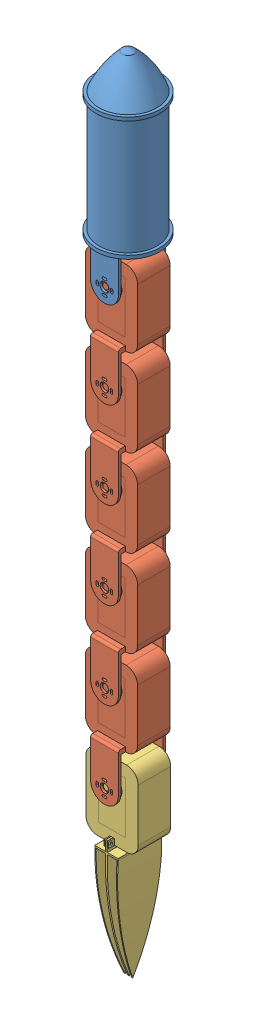
SolidWorks assembly bus_assembly_total_4, configuration 預設. Lengths in mm.
Overall size (647.03 670.77 55).
7 component instances, 3 part files, 24 mates.
Components (placement in the parent):
- base_link-2: base_link [預設] at (-200.3488 -8.0568 -97.9891) size (55 179.98 55)
- link1-1: link1 [預設] at (-286.3308 -349.3248 -5.4136) x (0 1 0) z (0 0 -1) size (45 107 40.5)
- link1-2: link1 [預設] at (-286.3308 -125.2248 -5.4136) x (0 1 0) z (0 0 -1) size (45 107 40.5)
- link1-3: link1 [預設] at (-286.3308 -199.9248 -5.4136) x (0 1 0) z (0 0 -1) size (45 107 40.5)
- link1-4: link1 [預設] at (-286.3308 -424.0248 -5.4136) x (0 1 0) z (0 0 -1) size (45 107 40.5)
- link1-5: link1 [預設] at (-286.3308 -274.6248 -5.4136) x (0 1 0) z (0 0 -1) size (45 107 40.5)
- link6-1: link6 [預設] at (-162.426 -442.9917 52.8279) x (0 1 0) z (0 0 -1) size (170.09 49.79 38.13)
Mates (geometry in assembly coordinates):
- 重合/共線/共點1: coincident: plane of base_link-2 through (-179.3308 -93.8197 20.2609) normal (0 0 -1); plane of link1-2 through (-179.3308 -93.8197 20.2609) normal (0 0 1)
- 重合/共線/共點2: coincident: plane of base_link-2 through (-179.3308 -93.8197 -16.2391) normal (0 0 1); plane of link1-2 through (-179.3308 -93.8197 -16.2391) normal (0 0 -1)
- 同軸心1: concentric: cylinder of base_link-2 through (-179.3308 -93.8197 20.2609) axis (0 0 1) radius 4; cylinder of link1-2 through (-179.3308 -93.8197 16.2609) axis (0 0 1) radius 4
- 重合/共線/共點3: coincident: plane of base_link-2 through (-180.3808 -86.6197 20.2609) normal (0 -1 0); plane of link1-2 through (-178.2808 -86.6197 16.2609) normal (0 -1 0)
- 重合/共線/共點4: coincident: plane of link1-2 through (-179.3308 -168.5197 20.2609) normal (0 0 -1); plane of link1-3 through (-179.3308 -168.5197 20.2609) normal (0 0 1)
- 重合/共線/共點5: coincident: plane of link1-2 through (-179.3308 -168.5197 -16.2391) normal (0 0 1); plane of link1-3 through (-179.3308 -168.5197 -16.2391) normal (0 0 -1)
- 同軸心2: concentric: cylinder of link1-2 through (-179.3308 -168.5197 -16.2391) axis (0 0 -1) radius 4; cylinder of link1-3 through (-179.3308 -168.5197 -17.2391) axis (0 0 1) radius 4
- 平行1: parallel: plane of link1-2 through (-172.2308 -169.5697 -16.2391) normal (-1 0 0); plane of link1-3 through (-172.1308 -169.5697 -17.2391) normal (-1 0 0)
- 重合/共線/共點7: coincident: plane of link1-3 through (-179.3308 -243.2197 -16.2391) normal (0 0 1); plane of link1-5 through (-179.3308 -243.2197 -16.2391) normal (0 0 -1)
- 重合/共線/共點8: coincident: plane of link1-3 through (-179.3308 -243.2197 20.2609) normal (0 0 -1); plane of link1-5 through (-179.3308 -243.2197 20.2609) normal (0 0 1)
- 同軸心3: concentric: cylinder of link1-3 through (-179.3308 -243.2197 22.2609) axis (0 0 -1) radius 3.7; cylinder of link1-5 through (-179.3308 -243.2197 16.2609) axis (0 0 1) radius 4
- 平行2: parallel: plane of link1-3 through (-178.2808 -236.1197 22.2609) normal (0 -1 0); plane of link1-5 through (-178.2808 -236.0197 16.2609) normal (0 -1 0)
- 重合/共線/共點10: coincident: plane of link1-1 through (-179.3308 -317.9197 20.2609) normal (0 0 1); plane of link1-5 through (-179.3308 -317.9197 20.2609) normal (0 0 -1)
- 重合/共線/共點11: coincident: plane of link1-1 through (-179.3308 -317.9197 -16.2391) normal (0 0 -1); plane of link1-5 through (-179.3308 -317.9197 -16.2391) normal (0 0 1)
- 同軸心4: concentric: cylinder of link1-1 through (-179.3308 -317.9197 16.2609) axis (0 0 1) radius 4; cylinder of link1-5 through (-179.3308 -317.9197 22.2609) axis (0 0 -1) radius 3.7
- 平行3: parallel: plane of link1-1 through (-178.2808 -310.7197 16.2609) normal (0 -1 0); plane of link1-5 through (-178.2808 -310.8197 22.2609) normal (0 -1 0)
- 重合/共線/共點13: coincident: plane of link1-1 through (-179.3308 -392.6197 20.2609) normal (0 0 -1); plane of link1-4 through (-179.3308 -392.6197 20.2609) normal (0 0 1)
- 重合/共線/共點14: coincident: plane of link1-1 through (-179.3308 -392.6197 -16.2391) normal (0 0 1); plane of link1-4 through (-179.3308 -392.6197 -16.2391) normal (0 0 -1)
- 同軸心5: concentric: cylinder of link1-1 through (-179.3308 -392.6197 -16.2391) axis (0 0 -1) radius 4; cylinder of link1-4 through (-179.3308 -392.6197 -17.2391) axis (0 0 1) radius 4
- 重合/共線/共點15: coincident: plane of link1-1 through (-178.2808 -397.8197 -16.2391) normal (0 -1 0); plane of link1-4 through (-178.2808 -397.8197 -17.2391) normal (0 -1 0)
- 重合/共線/共點16: coincident: plane of link1-4 through (-179.3308 -467.3197 20.2609) normal (0 0 -1); plane of link6-1 through (-179.3308 -467.3197 20.2609) normal (0 0 1)
- 平行4: parallel: plane of link1-4 through (-179.3308 -467.3197 -16.2391) normal (0 0 1); plane of link6-1 through (-179.3308 -467.3197 -16.7391) normal (0 0 -1)
- 同軸心7: concentric: cylinder of link1-4 through (-179.3308 -467.3197 22.2609) axis (0 0 -1) radius 3.7; cylinder of link6-1 through (-179.3308 -467.3197 16.2609) axis (0 0 1) radius 4
- 平行5: parallel: plane of link1-4 through (-178.2808 -460.2197 22.2609) normal (0 -1 0); plane of link6-1 through (-178.2808 -460.1197 16.2609) normal (0 -1 0)
